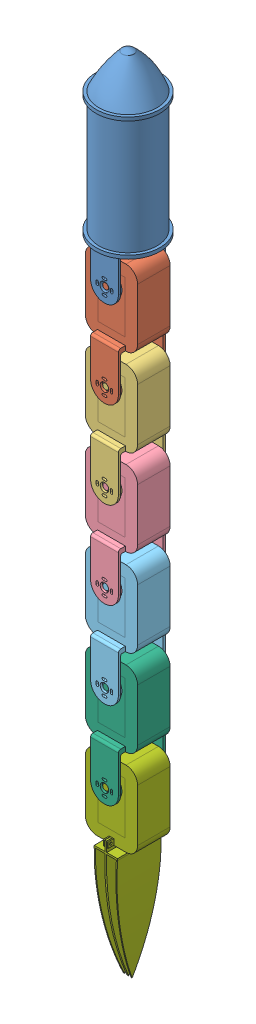
SolidWorks assembly test6, configuration 預設. Lengths in mm.
Overall size (55 691.27 55).
7 component instances, 7 part files, 25 mates.
Components (placement in the parent):
- base_link2-2: base_link2 [預設] at origin size (55 179.98 55)
- link1-1: link1 [預設] at (0 -157.7 0) x (0 1 0) z (0 0 -1) size (107 45 40.5)
- link2-1: link2 [預設] at (0 -232.4 0) x (0 1 0) z (0 0 -1) size (107 45 40.5)
- link3-2: link3 [預設] at (0 -307.1 0) x (0 1 0) z (0 0 -1) size (107 45 40.5)
- link4-1: link4 [預設] at (0 -381.8 0) x (0 1 0) z (0 0 -1) size (107 45 40.5)
- link5-1: link5 [預設] at (0 -456.5 0) x (0 1 0) z (0 0 -1) size (107 45 40.5)
- link6-1: link6 [預設] at (0 -456.2 0.5) x (0 1 0) z (0 0 -1) size (170.09 49.79 38.13)
Mates (geometry in assembly coordinates):
- 平行相距4: distance = 18.5 mm: plane of base_link2-2 through (0 -83 -18.5) normal (0 0 1); plane of assembly through (0 0 0) normal (0 0 1)
- 平行相距5: distance = 12 mm: plane of assembly through (0 0 0) normal (1 0 0); plane of base_link2-2 through (12 -53 18) normal (1 0 0)
- 平行相距6: distance = 50 mm: plane of assembly through (0 0 0) normal (0 1 0); plane of base_link2-2 through (0 -50 -0.25) normal (0 1 0)
- 同軸心2: concentric: cylinder of base_link2-2 through (0 -83 18) axis (0 0 1) radius 4; cylinder of link1-1 through (0 -83 14) axis (0 0 1) radius 2.5
- 同軸心3: concentric: cylinder of base_link2-2 through (0 -83 -20.5) axis (0 0 1) radius 4; cylinder of link1-1 through (0 -83 -19) axis (0 0 1) radius 2.5
- 平行1: parallel: plane of base_link2-2 through (12 -53 -20.5) normal (1 0 0); plane of link1-1 through (22.5 -127.7 -14) normal (1 0 0)
- 重合/共線/共點8: coincident: plane of base_link2-2 through (0 -83 -18.5) normal (0 0 1); plane of link1-1 through (0 -157.7 -18.5) normal (0 0 1)
- 同軸心4: concentric: cylinder of link1-1 through (0 -157.7 20) axis (0 0 -1) radius 3.7; cylinder of ? through (122.3295 -185.6512 7.75) axis (0 0 -1) radius 2.5
- 重合/共線/共點9: coincident: plane of link1-1 through (22.5 -127.7 -14) normal (1 0 0); plane of ?
- 重合/共線/共點10: coincident: plane of link1-1 through (0 -67.7653 20) normal (0 0 1); plane of ?
- 重合/共線/共點11: coincident: plane of link1-1 through (22.5 -127.7 -14) normal (1 0 0); plane of link2-1 through (22.5 -202.4 -14) normal (1 0 0)
- 同軸心5: concentric: cylinder of link1-1 through (0 -157.7 20) axis (0 0 -1) radius 3.7; cylinder of link2-1 through (0 -157.7 14) axis (0 0 1) radius 2.5
- 重合/共線/共點12: coincident: plane of link1-1 through (0 -67.7653 14) normal (0 0 1); plane of link2-1 through (0 -142.4653 14) normal (0 0 1)
- 重合/共線/共點14: coincident: plane of link2-1 through (22.5 -202.4 -14) normal (1 0 0); plane of link3-2 through (22.5 -277.1 -14) normal (1 0 0)
- 同軸心6: concentric: cylinder of link2-1 through (0 -232.4 -18.5) axis (0 0 -1) radius 4; cylinder of link3-2 through (0 -232.4 -19) axis (0 0 1) radius 2.5
- 重合/共線/共點15: coincident: plane of link2-1 through (0 -142.4653 -14) normal (0 0 -1); plane of link3-2 through (0 -217.1653 -14) normal (0 0 -1)
- 同軸心7: concentric: cylinder of link3-2 through (0 -307.1 20) axis (0 0 -1) radius 3.7; cylinder of link4-1 through (0 -307.1 14) axis (0 0 1) radius 2.5
- 重合/共線/共點16: coincident: plane of link3-2 through (22.5 -277.1 -14) normal (1 0 0); plane of link4-1 through (22.5 -351.8 -14) normal (1 0 0)
- 重合/共線/共點17: coincident: plane of link3-2 through (0 -217.1653 14) normal (0 0 1); plane of link4-1 through (0 -291.8653 14) normal (0 0 1)
- 重合/共線/共點18: coincident: plane of link4-1 through (22.5 -351.8 -14) normal (1 0 0); plane of link5-1 through (22.5 -426.5 -14) normal (1 0 0)
- 同軸心8: concentric: cylinder of link4-1 through (0 -381.8 20) axis (0 0 -1) radius 3.7; cylinder of link5-1 through (0 -381.8 14) axis (0 0 1) radius 2.5
- 重合/共線/共點19: coincident: plane of link4-1 through (0 -291.8653 14) normal (0 0 1); plane of link5-1 through (0 -366.5653 14) normal (0 0 1)
- 重合/共線/共點21: coincident: plane of link5-1 through (-22.5 -426.5 -14) normal (-1 0 0); plane of link6-1 through (-22.5 -501.2 -14) normal (-1 0 0)
- 同軸心9: concentric: cylinder of link5-1 through (0 -456.5 14) axis (0 0 1) radius 4; cylinder of link6-1 through (0 -456.5 14) axis (0 0 1) radius 2.5
- 重合/共線/共點22: coincident: plane of link5-1 through (0 -366.5653 14) normal (0 0 1); plane of link6-1 through (0 -441.2653 14) normal (0 0 1)
